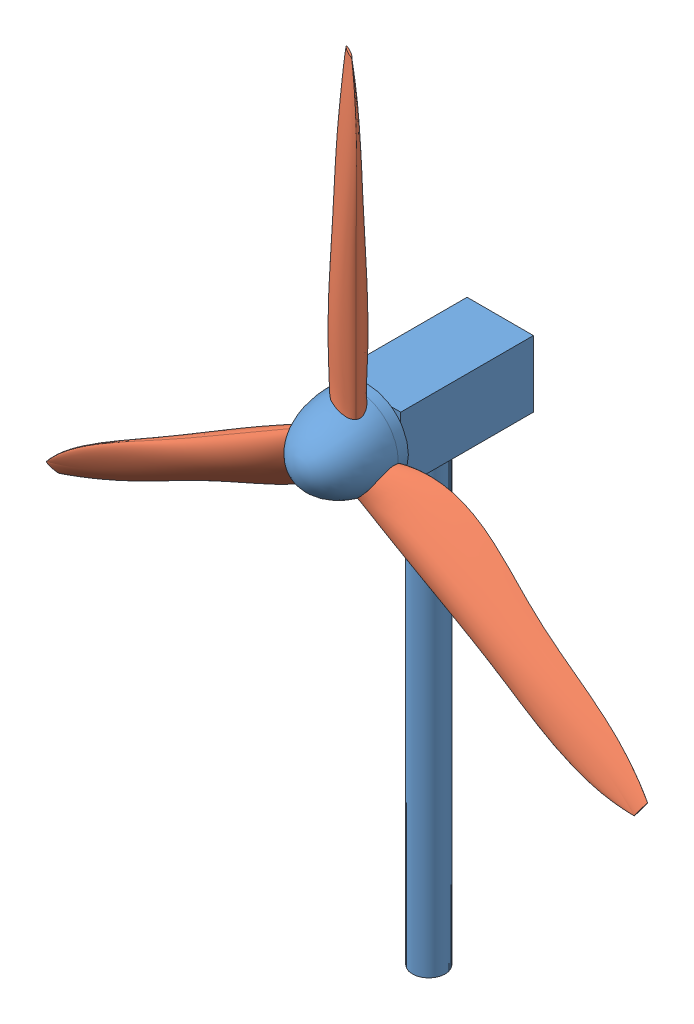
SolidWorks assembly turbie, configuration Default. Lengths in mm.
Overall size (614.99 815.03 200).
4 component instances, 2 part files, 3 mates.
Components (placement in the parent):
- Tower1-1: Tower1 [Default] at (216.1836 84.493 517.7478) size (80 522.5 200)
- blade-1: blade [Default] at (217.4586 599.493 597.2478) x (0.866025 0 0.5) z (0 1 0) size (73.31 29.13 300.04)
- blade-2: blade [Default] at (187.4003 551.8472 597.2478) x (-0.433013 0.75 0.5) z (-0.866025 -0.5 0) size (73.31 29.13 300.04)
- blade-3: blade [Default] at (243.6919 549.6388 597.2478) x (-0.433013 -0.75 0.5) z (0.866025 -0.5 0) size (73.31 29.13 300.04)
Mates (geometry in assembly coordinates):
- Coincident1: coincident anti-aligned: plane of Tower1-1 through (216.1836 599.493 517.7478) normal (0 1 0); plane of blade-1 through (217.4586 599.493 597.2478) normal (0 -1 0)
- Angle1: planar angle = 0.523599 rad aligned: line of blade-1 through (201.0041 599.493 587.7478) axis (0.866025 0 0.5); line of Tower1-1 through (192.8651 599.493 577.7478) axis (1 0 0)
- Distance1: distance = 29 mm: point of blade-1; line of Tower1-1 through (192.8651 599.493 577.7478) axis (1 0 0)
